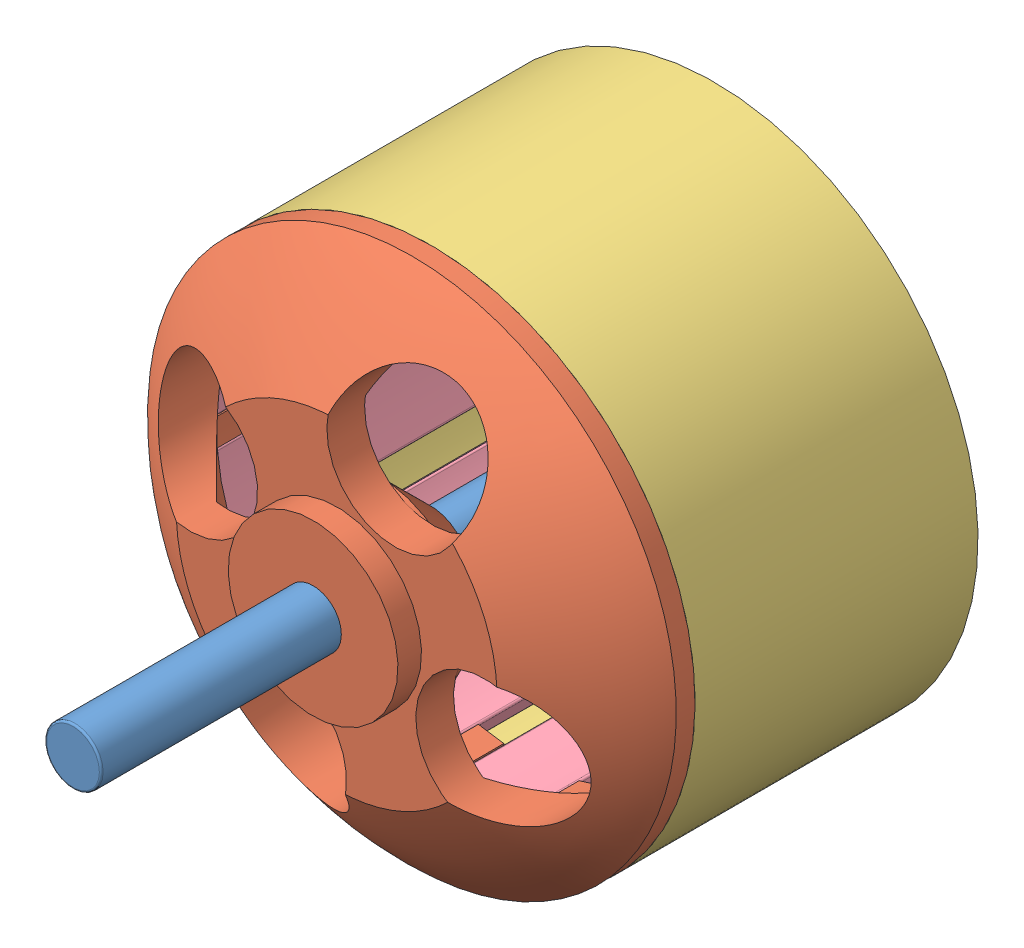
SolidWorks assembly motor_rotor, configuration Default. Lengths in mm.
Overall size (38.76 38.76 40).
17 component instances, 4 part files, 7 mates.
Components (placement in the parent):
- shaft-1: shaft [Default] at (42.4959 18.6707 -31.1458) size (3 3 40)
- rotor_part-1: rotor_part [Default] at (42.4959 18.6707 -25.1237) x (0.930002 -0.367555 0) z (0 0 1) size (28 28 11.25)
- ring-2: ring [Default] at (42.4959 18.6707 -25.1237) x (0.836625 -0.547775 0) z (0 0 1) size (28 28 15)
- magnet-16: magnet [Default] at (42.4959 18.6707 -24.1237) x (0.997379 0.072352 0) z (0 0 1) size (4 1.15 14)
- magnet-17: magnet [Default] at (42.4959 18.6707 -24.1237) x (0.867216 0.497932 0) z (0 0 1) size (4 1.15 14)
- magnet-18: magnet [Default] at (42.4959 18.6707 -24.1237) x (0.565292 0.824891 0) z (0 0 1) size (4 1.15 14)
- magnet-19: magnet [Default] at (42.4959 18.6707 -24.1237) x (0.151405 0.988472 0) z (0 0 1) size (4 1.15 14)
- magnet-20: magnet [Default] at (42.4959 18.6707 -24.1237) x (-0.29247 0.956275 0) z (0 0 1) size (4 1.15 14)
- magnet-21: magnet [Default] at (42.4959 18.6707 -24.1237) x (-0.678417 0.734677 0) z (0 0 1) size (4 1.15 14)
- magnet-22: magnet [Default] at (42.4959 18.6707 -24.1237) x (-0.929996 0.367568 0) z (0 0 1) size (4 1.15 14)
- magnet-23: magnet [Default] at (42.4959 18.6707 -24.1237) x (-0.99738 -0.072341 0) z (0 0 1) size (4 1.15 14)
- magnet-24: magnet [Default] at (42.4959 18.6707 -24.1237) x (-0.867221 -0.497923 0) z (0 0 1) size (4 1.15 14)
- magnet-25: magnet [Default] at (42.4959 18.6707 -24.1237) x (-0.5653 -0.824885 0) z (0 0 1) size (4 1.15 14)
- magnet-26: magnet [Default] at (42.4959 18.6707 -24.1237) x (-0.151415 -0.98847 0) z (0 0 1) size (4 1.15 14)
- magnet-27: magnet [Default] at (42.4959 18.6707 -24.1237) x (0.29246 -0.956278 0) z (0 0 1) size (4 1.15 14)
- magnet-28: magnet [Default] at (42.4959 18.6707 -24.1237) x (0.678409 -0.734684 0) z (0 0 1) size (4 1.15 14)
- magnet-29: magnet [Default] at (42.4959 18.6707 -24.1237) x (0.929993 -0.367578 0) z (0 0 1) size (4 1.15 14)
Mates (geometry in assembly coordinates):
- Concentric6: concentric: cylinder of assembly; cylinder of assembly; cylinder of shaft-1 through (42.4959 18.6707 8.8542) axis (0 0 -1) radius 1.5; cylinder of rotor_part-1 through (42.4959 18.6707 -21.8737) axis (0 0 1) radius 1.5
- Concentric7: concentric: cylinder of assembly; cylinder of assembly; cylinder of rotor_part-1 through (42.4959 18.6707 -10.1237) axis (0 0 -1) radius 13; cylinder of ring-2 through (42.4959 18.6707 -10.1237) axis (0 0 -1) radius 13
- Coincident6: coincident: plane of assembly; plane of assembly; plane of rotor_part-1 through (42.4959 18.6707 -10.1237) normal (0 0 -1); plane of ring-2 through (42.4959 18.6707 -10.1237) normal (0 0 1)
- Concentric8: concentric: cylinder of assembly; cylinder of assembly; cylinder of ring-2 through (42.4959 18.6707 -10.1237) axis (0 0 -1) radius 13; cylinder of magnet-16 through (42.4959 18.6707 -10.1237) axis (0 0 -1) radius 13
- Coincident7: coincident: plane of assembly; plane of assembly; plane of rotor_part-1 through (42.4959 18.6707 -10.1237) normal (0 0 -1); plane of magnet-16 through (42.4959 18.6707 -10.1237) normal (0 0 1)
- Coincident8: coincident: plane of assembly; plane of assembly; plane of rotor_part-1 through (39.6451 30.3271 -10.1237) normal (0.997379 0.072352 0); plane of magnet-16 through (39.6451 30.3271 -10.1237) normal (-0.997379 -0.072352 0)
- Concentric9: concentric: cylinder of assembly; cylinder of assembly; cylinder of shaft-1 through (42.4959 18.6707 8.8542) axis (0 0 -1) radius 1.5; cylinder of rotor_part-1 through (42.4959 18.6707 -21.8737) axis (0 0 1) radius 1.5
